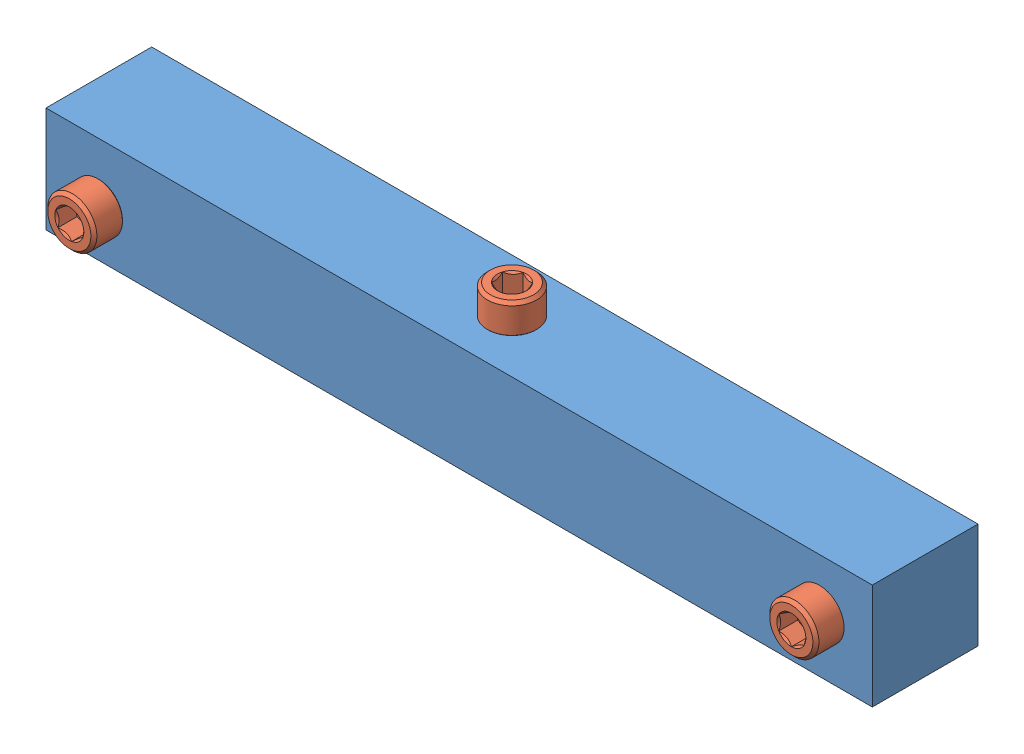
SolidWorks assembly Bracket, Hydrophone, configuration Default. Lengths in mm.
Overall size (78.2 15.68 15.81).
4 component instances, 2 part files, 3 mates.
Components (placement in the parent):
- DIY Wonky Bracket-1: DIY Wonky Bracket [Default] at origin size (78.2 10 10)
- SHCS-4: SHCS [0.5, #4-40] at (-5 5.1542 3.4686) x (0 0 -1) z (1 0 0) size (15.68 4.65 4.65)
- SHCS-5: SHCS [0.5, #4-40] at (-73.199 4.4145 3.5992) x (0 0 -1) z (0.360911 0.9326 0) size (15.68 4.65 4.65)
- SHCS-6: SHCS [0.5, #4-40] at (-39.1 3.5588 5) x (0 -1 0) z (-0.294895 0 0.95553) size (15.68 4.65 4.65)
Mates (geometry in assembly coordinates):
- Concentric12: concentric anti-aligned: cylinder of DIY Wonky Bracket-1 through (-5 5.1542 10) axis (0 0 1) radius 1.45; cylinder of SHCS-4 through (-5 5.1542 9.8186) axis (0 0 -1) radius 1.4224
- Concentric22: concentric anti-aligned: cylinder of DIY Wonky Bracket-1 through (-39.1 10 5) axis (0 1 0) radius 1.45; cylinder of SHCS-6 through (-39.1 9.9088 5) axis (0 -1 0) radius 1.4224
- Concentric23: concentric anti-aligned: cylinder of DIY Wonky Bracket-1 through (-73.199 4.4145 10) axis (0 0 1) radius 1.45; cylinder of SHCS-5 through (-73.199 4.4145 9.9492) axis (0 0 -1) radius 2.3241
